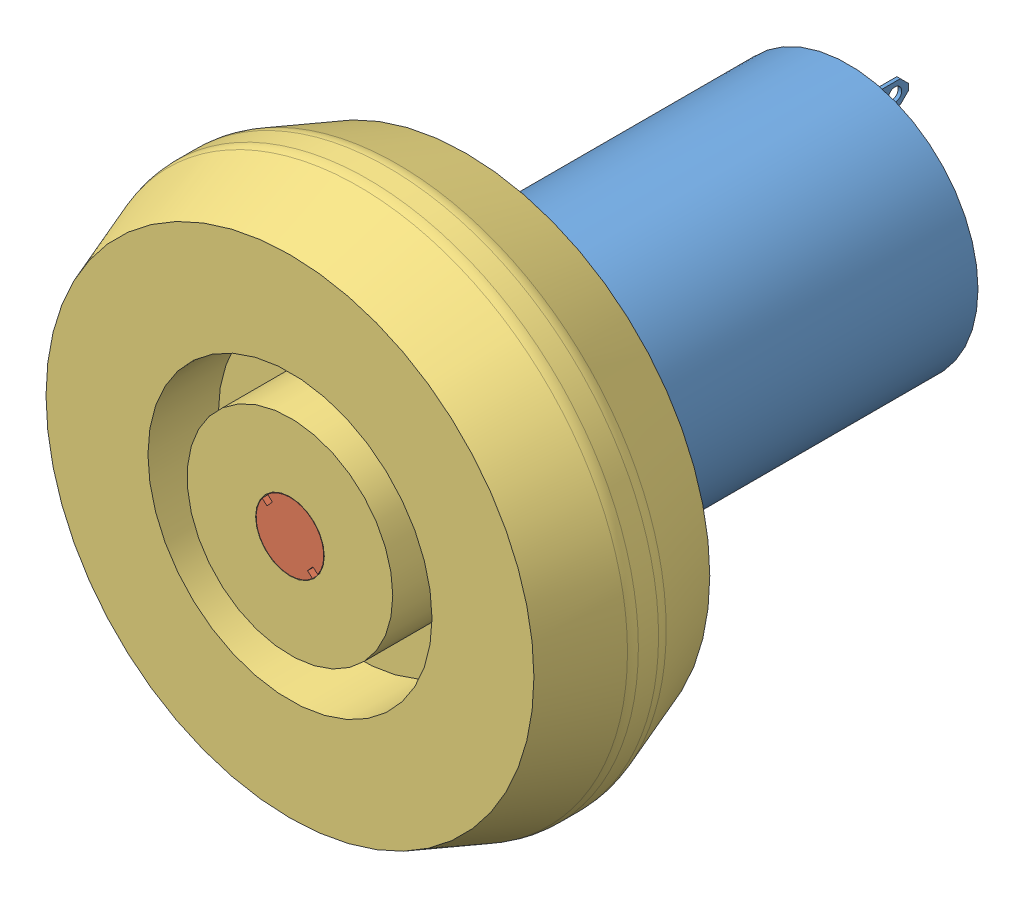
SolidWorks assembly Assem1, configuration Default. Lengths in mm.
Overall size (50.8 50.8 56.46).
3 component instances, 3 part files, 4 mates.
Components (placement in the parent):
- DC_Motor-1: DC_Motor [Default] at (16.24 25.168 15.283) size (24.38 24.38 45.03)
- MotorShaft-1: MotorShaft [Default] at (16.24 25.168 67.6832) x (0.749535 -0.661965 0) z (0.661965 0.749535 0) size (6.3 19.05 6.35)
- Omni_Wheel-1: Omni_Wheel [Default] at (16.24 25.168 59.4282) size (50.8 50.8 16.51)
Mates (geometry in assembly coordinates):
- Concentric1: concentric aligned: cylinder of DC_Motor-1 through (16.24 25.168 56.2532) axis (0 0 -1) radius 0.9969; cylinder of MotorShaft-1 through (16.24 25.168 56.2532) axis (0 0 -1) radius 1.0033
- Coincident1: coincident anti-aligned: plane of DC_Motor-1 through (16.24 25.168 56.2532) normal (0 0 1); plane of MotorShaft-1 through (16.24 25.168 56.2532) normal (0 0 -1)
- Coincident2: coincident: plane of MotorShaft-1 through (16.24 25.168 67.6832) normal (0 0 1); plane of Omni_Wheel-1 through (16.24 25.168 67.6832) normal (0 0 1)
- Concentric3: concentric aligned: cylinder of MotorShaft-1 through (16.24 25.168 48.6332) axis (0 0 1) radius 3.175; cylinder of Omni_Wheel-1 through (16.24 25.168 51.1732) axis (0 0 1) radius 3.2258
